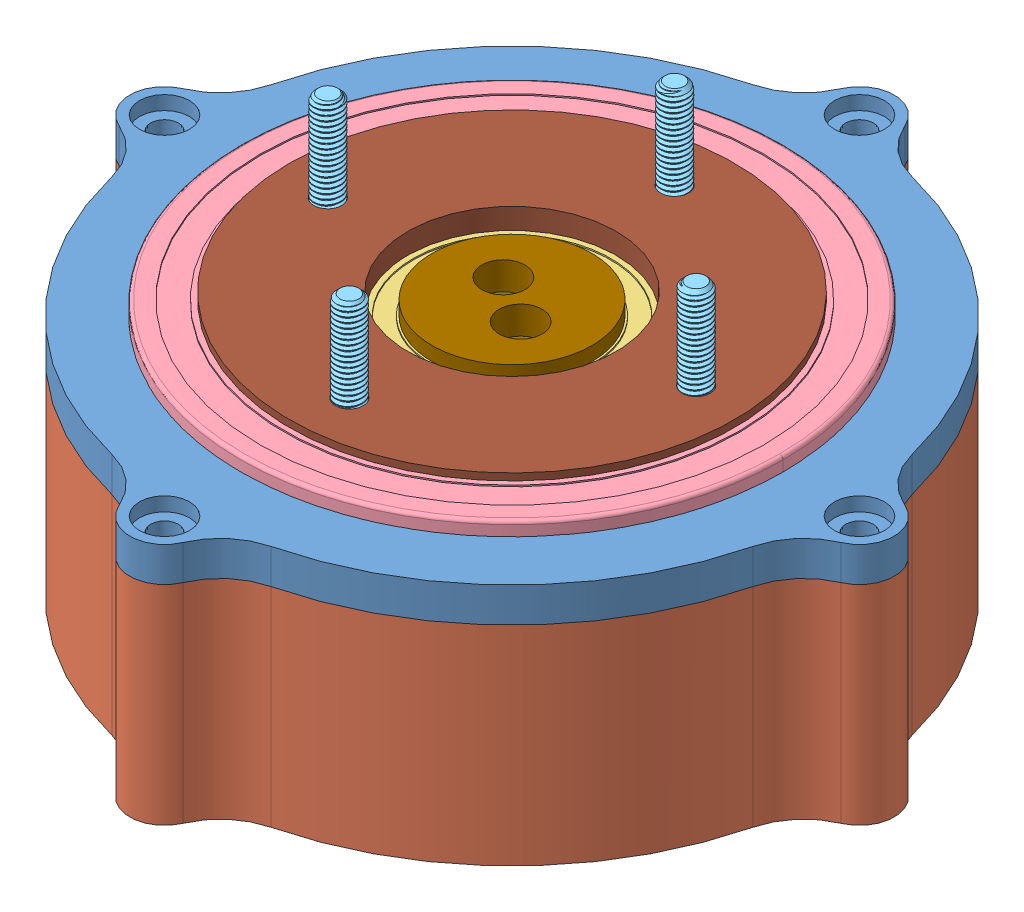
SolidWorks assembly Cycloidal Drive v1.3, configuration Default. Lengths in mm.
Overall size (110 54 110).
29 component instances, 14 part files, 40 mates.
Components (placement in the parent):
- Top v1.1-2: Top v1.1 [Default] at (0 33 0) x (1 0 0) z (0 1 0) size (110 110 9)
- Housing v1.4-1: Housing v1.4 [Default] at origin size (110 30 110)
- 6804-3: 6804 [Default] at (-2.113 16.5128 -1.3361) x (0 1 0) z (0.334381 0 -0.942438) size (7.01 32.02 32)
- 6804-2: 6804 [Default] at (0 34.5024 0) x (0 1 0) z (-0.979902 0 -0.199479) size (7.01 32.02 32)
- 6804-1: 6804 [Default] at (2.113 24.5024 1.3361) x (0 1 0) z (0.500985 0 0.865456) size (7.01 32.02 32)
- 6812-1: 6812 [Default] at (0 5.9962 0) x (0 1 0) z (0 0 -1) size (10.01 78 78)
- 6812-2: 6812 [Default] at (0 35.0038 0) x (0 -1 0) z (0 0 1) size (10.01 78 78)
- M4_50-1: M4_50 [Default] at (25.8388 -66.0076 211.2918) x (-0.063005 0 -0.998013) z (0.998013 0 -0.063005) size (7.2 54 7.2)
- M4_50-2: M4_50 [Default] at (-211.2918 -66.0076 25.8388) x (0.998013 0 -0.063005) z (0.063005 0 0.998013) size (7.2 54 7.2)
- M4_50-3: M4_50 [Default] at (-25.8388 -66.0076 -211.2918) x (0.063005 0 0.998013) z (-0.998013 0 0.063005) size (7.2 54 7.2)
- M4_50-4: M4_50 [Default] at (211.2918 -66.0076 -25.8388) x (-0.998013 0 0.063005) z (-0.063005 0 -0.998013) size (7.2 54 7.2)
- Eccentric Shaft Assembly-1: Eccentric Shaft Assembly [Default] at (0 0.0076 0) x (-0.845204 0 -0.534444) z (0.534444 0 -0.845204) size (36 40 36)
  - Eccentric Shaft Bottom-1: Eccentric Shaft Bottom [Default] at origin size (36 21 36)
  - Eccentric Shaft Middle-1: Eccentric Shaft Middle [Default] at origin size (24.3 11 22)
  - Eccentric Shaft Top-1: Eccentric Shaft Top [Default] at origin size (23.5 10 22)
  - Eccentric Shaft Cap-1: Eccentric Shaft Cap [Default] at origin size (23 5 23)
- BottomCap v1.2-1: BottomCap v1.2 [Default] at (0 -0.0076 0) x (-0.99795 0 0.064003) z (0 -1 0) size (63.99 63.99 11)
- TopCap v1.2-1: TopCap v1.2 [Default] at (0 38.0076 0) x (0.998076 0 -0.062007) z (0 1 0) size (63.99 63.99 10)
- Dowel Pin-10: Dowel Pin [Default] at (43 5.4 0) x (0.827231 0 0.561862) z (-0.561862 0 0.827231) size (6 30 6)
- Dowel Pin-11: Dowel Pin [Default] at (32.9399 5.4 -27.6399) x (0.994854 0 -0.101322) z (0.101322 0 0.994854) size (6 30 6)
- Dowel Pin-12: Dowel Pin [Default] at (7.4669 5.4 -42.3467) x (0.696973 0 -0.717097) z (0.717097 0 0.696973) size (6 30 6)
- Dowel Pin-13: Dowel Pin [Default] at (-21.5 5.4 -37.2391) x (0.072972 0 -0.997334) z (0.997334 0 0.072972) size (6 30 6)
- Dowel Pin-14: Dowel Pin [Default] at (-40.4068 5.4 -14.7069) x (-0.585174 0 -0.810907) z (0.810907 0 -0.585174) size (6 30 6)
- Dowel Pin-15: Dowel Pin [Default] at (-40.4068 5.4 14.7069) x (-0.969511 0 -0.245048) z (0.245048 0 -0.969511) size (6 30 6)
- Dowel Pin-16: Dowel Pin [Default] at (-21.5 5.4 37.2391) x (-0.900202 0 0.435472) z (-0.435472 0 -0.900202) size (6 30 6)
- Dowel Pin-17: Dowel Pin [Default] at (7.4669 5.4 42.3467) x (-0.409679 0 0.91223) z (-0.91223 0 -0.409679) size (6 30 6)
- Dowel Pin-18: Dowel Pin [Default] at (32.9399 5.4 27.6399) x (0.272537 0 0.962145) z (-0.962145 0 0.272537) size (6 30 6)
- Cycloid v1.5-1: Cycloid v1.5 [Default] at (-2.113 13.018 -1.3361) x (0.954708 0 0.297544) z (-0.297544 0 0.954708) size (80.42 7.01 80.42)
- Cycloid 2 v1.5-1: Cycloid 2 v1.5 [Default] at (2.113 21.0076 1.3361) x (0.996828 0 -0.07959) z (0.07959 0 0.996828) size (80.42 7.01 80.42)
Mates (geometry in assembly coordinates):
- Concentric3: concentric: cylinder of ? through (1.8177 13 -1.7164) axis (0 1 0) radius 16; cylinder of ? through (1.8177 12.6391 -1.7164) axis (0 -1 0) radius 16.002
- Coincident2: coincident: plane of ? through (9.6469 20 -38.39) normal (0 1 0); plane of ? through (1.8177 20 -1.7164) normal (0 1 0)
- Concentric4: concentric: cylinder of assembly; cylinder of assembly; cylinder of Housing v1.4-1 through (0 -1 0) axis (0 1 0) radius 39; cylinder of 6812-1 through (0 0.492 0) axis (0 -1 0) radius 39.0017
- Distance1: distance = 2 mm: plane of 6812-1 through (0 11 0) normal (0 1 0); plane of ? through (9.6469 13 -38.39) normal (0 -1 0)
- Concentric5: concentric: cylinder of ? through (0 31.0076 0) axis (0 1 0) radius 16; cylinder of ? through (0 30.6467 0) axis (0 -1 0) radius 16.002
- Coincident6: coincident: plane of ? through (-13.9691 38.0076 -34.8011) normal (0 1 0); plane of ? through (0 38.0076 0) normal (0 1 0)
- Coincident36: coincident: plane of ? through (0 30 0) normal (0 1 0); plane of 6812-2 through (0 30 0) normal (0 -1 0)
- Concentric40: concentric: cylinder of assembly; cylinder of assembly; cylinder of 6812-1 through (0 0.492 0) axis (0 -1 0) radius 29.9974; cylinder of BottomCap v1.2-1 through (0 9.9924 0) axis (0 -1 0) radius 29.9974
- Coincident37: coincident: plane of assembly; plane of assembly; plane of 6812-1 through (0 0.9924 0) normal (0 -1 0); plane of BottomCap v1.2-1 through (0 0.9924 0) normal (0 1 0)
- Parallel1: parallel: plane of ? through (0 38 0) normal (0 1 0); plane of TopCap v1.2-1 through (0 31.0076 0) normal (0 -1 0)
- Concentric42: concentric: cylinder of assembly; cylinder of assembly; cylinder of 6812-2 through (0 40.508 0) axis (0 1 0) radius 29.9974; cylinder of TopCap v1.2-1 through (0 31.0076 0) axis (0 1 0) radius 29.9974
- Concentric43: concentric: cylinder of ? through (0 38 0) axis (0 -1 0) radius 39; cylinder of 6812-2 through (0 40.508 0) axis (0 1 0) radius 39.0017
- Coincident39: coincident: plane of assembly; plane of assembly; plane of 6812-2 through (0 40.0076 0) normal (0 1 0); plane of TopCap v1.2-1 through (0 40.0076 0) normal (0 -1 0)
- Concentric44: concentric: circle of assembly; cylinder of assembly; circle of M4_50-1; cylinder of TopCap v1.2-1 through (1.5502 28.0076 24.9519) axis (0 1 0) radius 2
- Coincident40: coincident: plane of assembly; plane of assembly; plane of M4_50-1 through (1.6001 3.9924 24.9487) normal (0 1 0); plane of BottomCap v1.2-1 through (1.6001 3.9924 24.9487) normal (0 -1 0)
- Coincident41: coincident: plane of assembly; plane of assembly; plane of Housing v1.4-1 through (0 11 0) normal (0 -1 0); plane of 6812-1 through (0 11 0) normal (0 1 0)
- Concentric45: concentric: cylinder of assembly; cylinder of Housing v1.4-1 through (0 -1 0) axis (0 1 0) radius 39; cylinder of 6812-1 through (0 0.492 0) axis (0 -1 0) radius 39.0017
- Coincident42: coincident: plane of ? through (0 33 0) normal (0 -1 0); plane of Housing v1.4-1 through (0 33 0) normal (0 1 0)
- Concentric49: concentric: cylinder of 6804-3 through (-2.113 12.6571 -1.3361) axis (0 -1 0) radius 9.9949; cylinder of ? through (-2.113 20.0076 -1.3361) axis (0 -1 0) radius 10
- Concentric50: concentric: cylinder of 6812-1 through (0 0.492 0) axis (0 -1 0) radius 29.9974; cylinder of ? through (0 10.0076 0) axis (0 -1 0) radius 18
- Concentric51: concentric: cylinder of 6804-1 through (2.113 20.6467 1.3361) axis (0 -1 0) radius 9.9949; cylinder of ? through (2.113 30.0076 1.3361) axis (0 -1 0) radius 10
- Concentric52: concentric: cylinder of 6804-2 through (0 30.6467 0) axis (0 -1 0) radius 9.9949; cylinder of ? through (0 38.0076 0) axis (0 -1 0) radius 10
- Coincident45: coincident: plane of assembly; plane of assembly; plane of 6804-2 through (0 38.0076 0) normal (0 1 0); plane of TopCap v1.2-1 through (0 38.0076 0) normal (0 -1 0)
- Coincident46: coincident: plane of 6804-2 through (0 38.0076 0) normal (0 1 0); plane of ? through (0 38.0076 0) normal (0 1 0)
- Coincident48: coincident: plane of 6804-1 through (2.113 28.0076 1.3361) normal (0 1 0); plane of ? through (0 28.0076 0) normal (0 -1 0)
- Coincident49: coincident: plane of 6804-3 through (-2.113 13.0076 -1.3361) normal (0 -1 0); plane of ? through (-2.113 13.0076 -1.3361) normal (0 1 0)
- Concentric53: concentric: cylinder of assembly; cylinder of assembly; cylinder of M4_50-2 through (-24.9487 -0.0076 1.6001) axis (0 1 0) radius 3.6; cylinder of BottomCap v1.2-1 through (-24.9487 3.9924 1.6001) axis (0 -1 0) radius 3.75
- Concentric54: concentric: cylinder of assembly; cylinder of assembly; cylinder of M4_50-1 through (1.6001 -0.0076 24.9487) axis (0 1 0) radius 3.6; cylinder of BottomCap v1.2-1 through (1.6001 3.9924 24.9487) axis (0 -1 0) radius 3.75
- Coincident50: coincident: plane of assembly; plane of assembly; plane of Housing v1.4-1 through (43 5.4 0) normal (0 1 0); plane of Dowel Pin-10 through (43 5.4 0) normal (0 -1 0)
- Concentric55: concentric: cylinder of assembly; cylinder of assembly; cylinder of Housing v1.4-1 through (43 2.5 0) axis (0 1 0) radius 3.15; cylinder of Dowel Pin-10 through (43 35.4 0) axis (0 -1 0) radius 3
- Concentric56: concentric: cylinder of assembly; cylinder of assembly; cylinder of 6804-1 through (2.113 20.6467 1.3361) axis (0 -1 0) radius 16.002; cylinder of Cycloid 2 v1.5-1 through (2.113 21.0076 1.3361) axis (0 1 0) radius 16
- Coincident51: coincident: plane of assembly; plane of assembly; plane of 6804-1 through (2.113 28.0076 1.3361) normal (0 1 0); plane of Cycloid 2 v1.5-1 through (-0.8716 28.0076 -36.0449) normal (0 1 0)
- Tangent2: tangent: cylinder of assembly; cylinder of Dowel Pin-11 through (32.9399 35.4 -27.6399) axis (0 -1 0) radius 3; face of Cycloid 2 v1.5-1
- Tangent5: tangent: cylinder of assembly; cylinder of Dowel Pin-10 through (43 35.4 0) axis (0 -1 0) radius 3; face of Cycloid 2 v1.5-1
- Tangent6: tangent: cylinder of assembly; cylinder of assembly; cylinder of M4_50-2 through (-24.9487 4.4924 1.6001) axis (0 -1 0) radius 1.95; cylinder of Cycloid 2 v1.5-1 through (-22.8077 31.0076 3.3259) axis (0 -1 0) radius 4.7
- Concentric58: concentric: cylinder of assembly; cylinder of assembly; cylinder of 6804-3 through (-2.113 12.6571 -1.3361) axis (0 -1 0) radius 16.002; cylinder of Cycloid v1.5-1 through (-2.113 13.018 -1.3361) axis (0 1 0) radius 16
- Coincident52: coincident: plane of 6804-3 through (-2.113 20.018 -1.3361) normal (0 1 0); plane of Cycloid v1.5-1 through (9.0449 20.018 -37.1377) normal (0 1 0)
- Tangent7: tangent: cylinder of Dowel Pin-17 through (7.4669 35.4 42.3467) axis (0 -1 0) radius 3; edge_curve of Cycloid v1.5-1
- Concentric59: concentric: cylinder of ? through (0 200.6346 0) axis (0 -1 0) radius 47.5; cylinder of Housing v1.4-1 through (0 -166.7056 0) axis (0 1 0) radius 47.5
- Concentric60: concentric: cylinder of assembly; cylinder of assembly; cylinder of Top v1.1-2 through (50 36 0) axis (0 1 0) radius 3.6; cylinder of Housing v1.4-1 through (50 -9.6134 0) axis (0 1 0) radius 2
